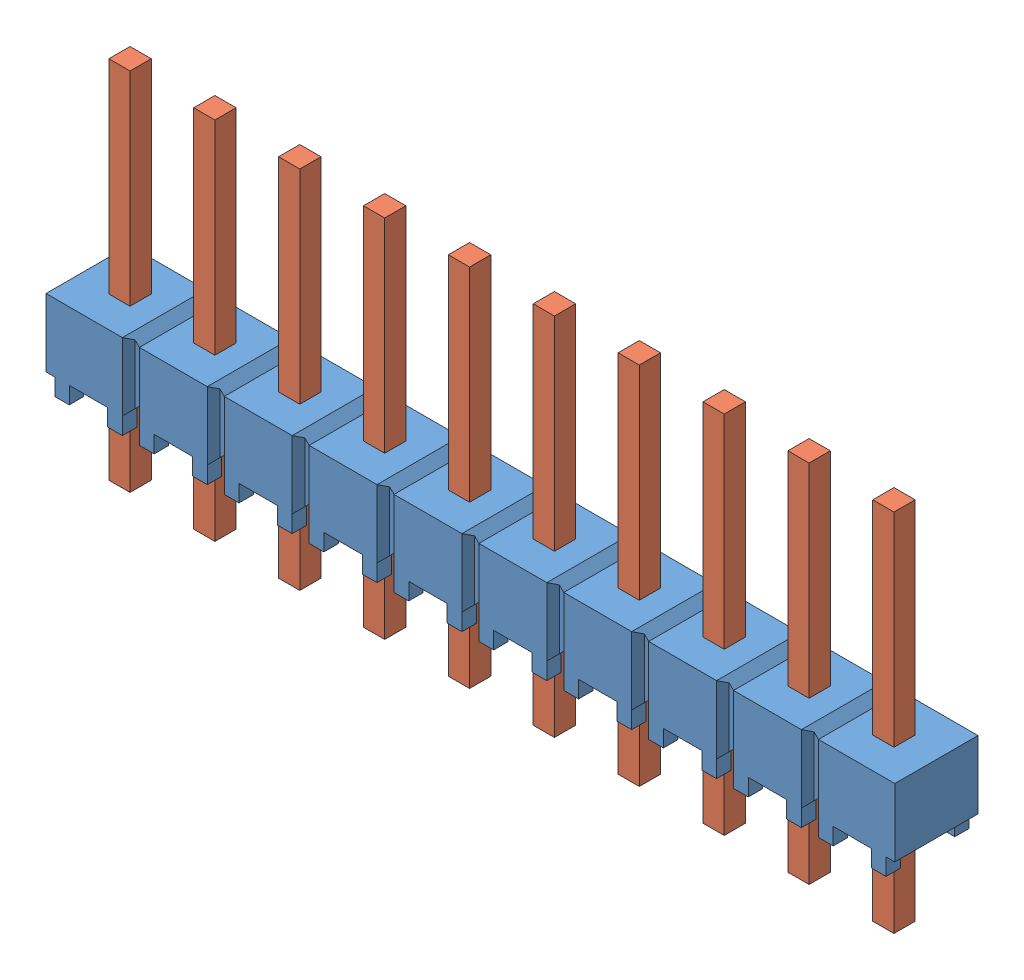
SolidWorks assembly HMTSW_110_07_G_S_240, configuration Default. Lengths in mm.
Overall size (25.4 10.92 2.49).
2 component instances, 2 part files, 0 mates.
Components (placement in the parent):
- _HMTSW_110_07_G_S_240_body_2-1: _HMTSW_110_07_G_S_240_body_2 [Default] at origin size (25.4 2.54 2.49)
- _HMTSW_110_07_S_240_4-1: _HMTSW_110_07_S_240_4 [Default] at (0 -2.286 0) size (23.75 10.92 0.89)
